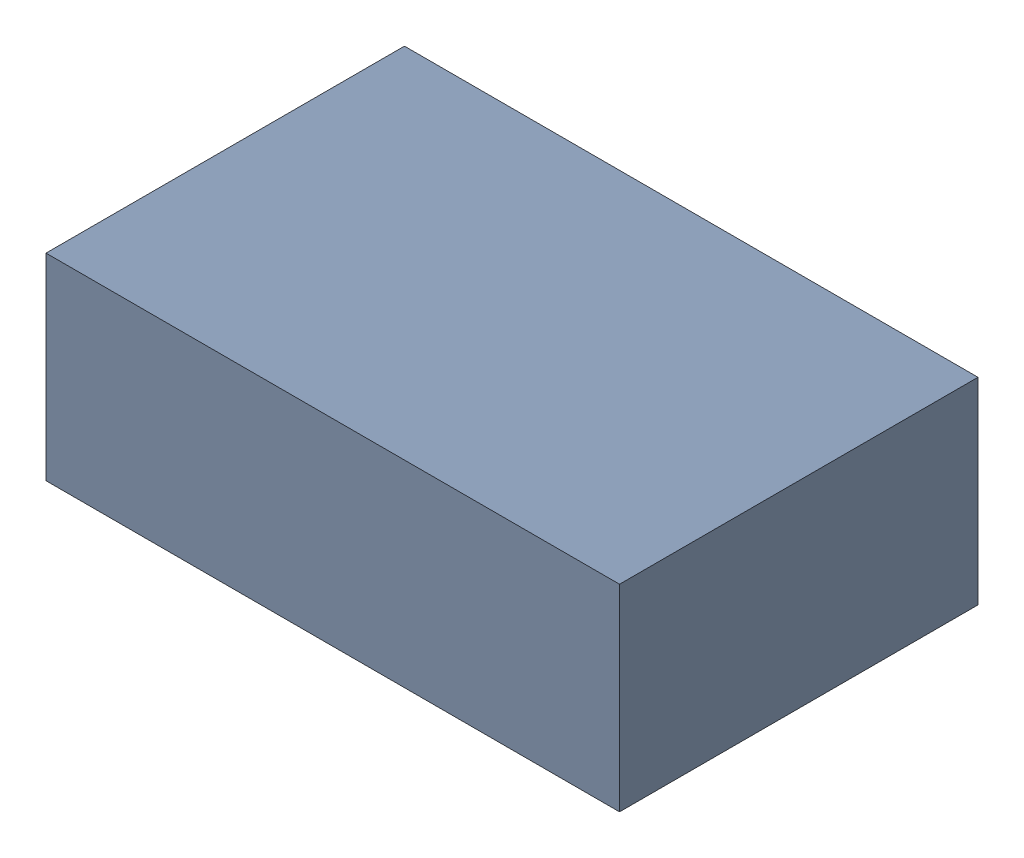
SolidWorks assembly C1, configuration Default. Lengths in mm.
Overall size (32 11 20).
2 component instances, 1 part files, 0 mates.
Components (placement in the parent):
- 809728768-1: 809728768 [Default] at (70.6473 112.522 0) size (32 11 20)
  - Extruded_4-1: Extruded_4 [Default] at origin size (32 11 20)
